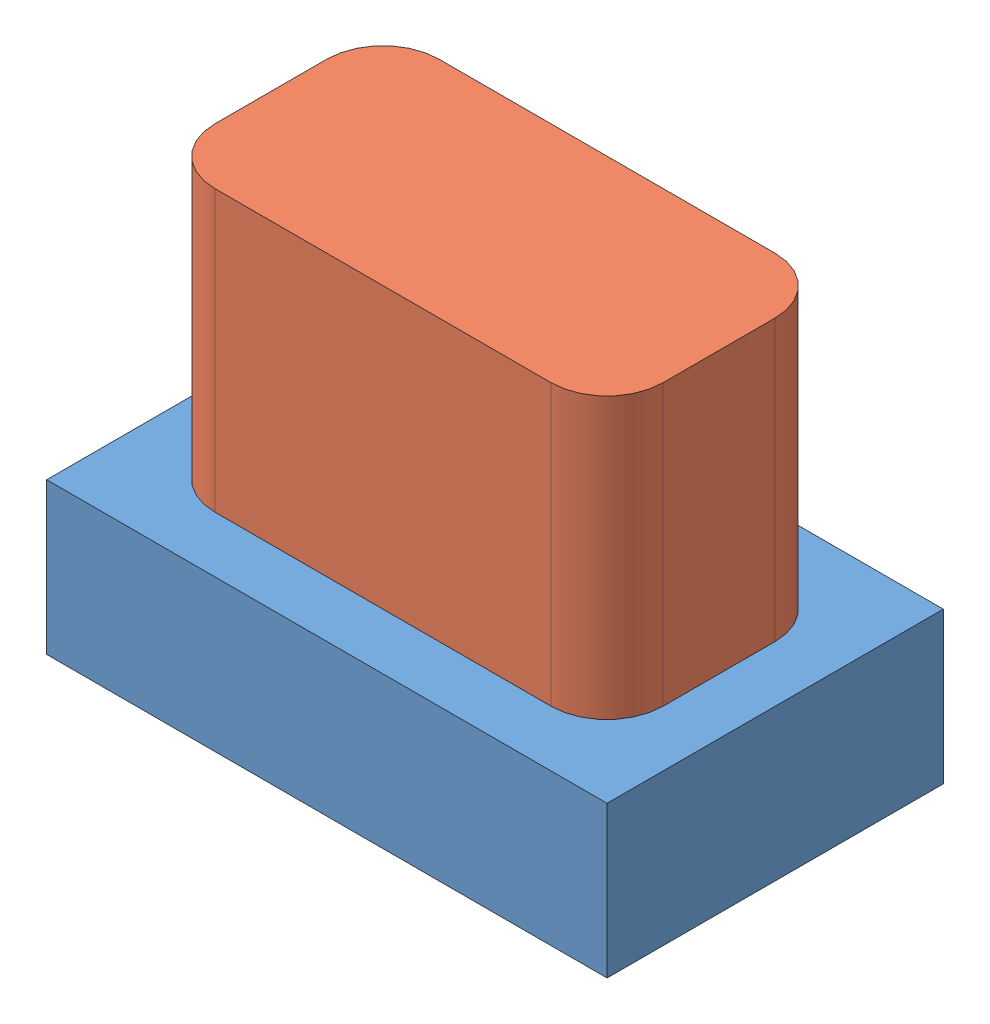
SolidWorks assembly Assem1, configuration Default. Lengths in mm.
Overall size (10 7.7 6).
2 component instances, 2 part files, 3 mates.
Components (placement in the parent):
- bb1-1: bb1 [Default] at (3.5396 3.7439 7.8625) size (10 2.7 6)
- bt1-1: bt1 [Default] at (3.5396 6.4439 7.8625) size (8 5 4)
Mates (geometry in assembly coordinates):
- Coincident1: coincident: plane of bb1-1 through (3.5396 6.4439 7.8625) normal (0 1 0); plane of bt1-1 through (0.5396 6.4439 1.8625) normal (0 -1 0)
- Distance1: distance = 1 mm: line of bt1-1 through (7.5396 6.4439 8.8625) axis (0 0 -1); line of bb1-1 through (8.5396 6.4439 10.8625) axis (0 0 -1)
- Distance6: distance = 1 mm: line of bt1-1 through (0.5396 6.4439 9.8625) axis (1 0 0); line of bb1-1 through (-1.4604 6.4439 10.8625) axis (1 0 0)
